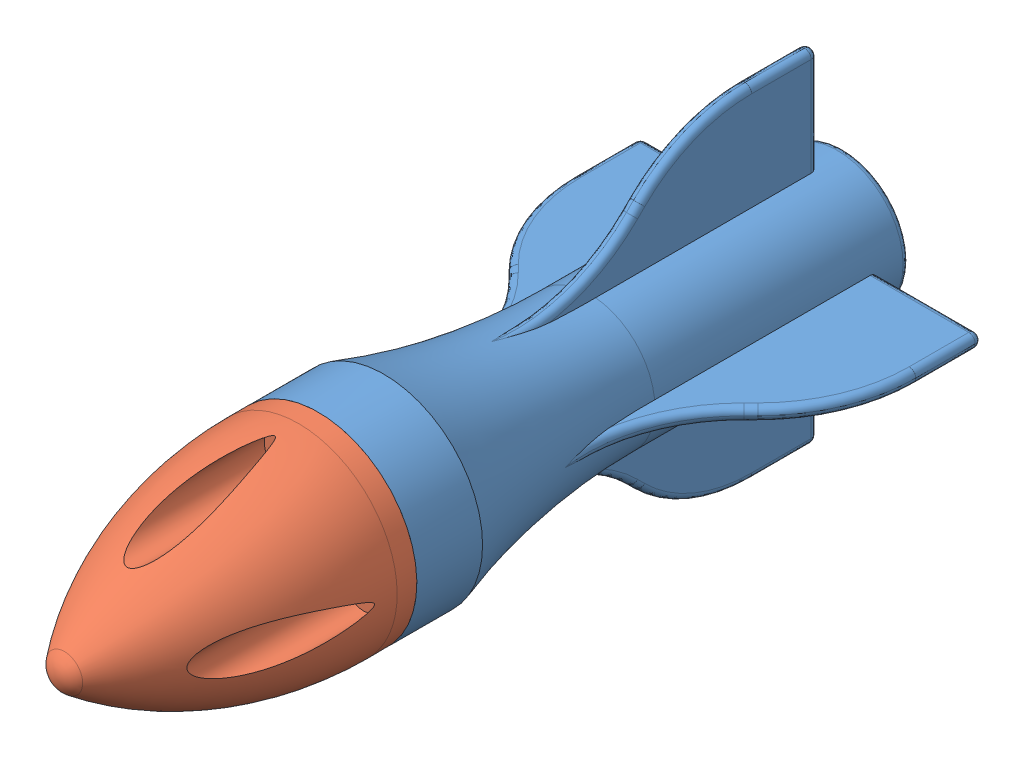
SolidWorks assembly MS-A-0043-TorpedoBodyAssem, configuration Default. Lengths in mm.
Overall size (65.99 65.99 152.4).
3 component instances, 3 part files, 3 mates.
Components (placement in the parent):
- MS-P-0042-Torpedo_Body-1: MS-P-0042-Torpedo_Body [Default] at (39.7527 50.552 32.0284) size (65.99 65.99 101.6)
- MS-P-0041-AltNoseCone-1: MS-P-0041-AltNoseCone [Default] at (39.7527 50.552 133.6284) x (0.018853 -0.999822 0) z (-0.999822 -0.018853 0) size (38.1 62.23 38.1)
- 9557K116_STEAM-RESISTANT EPDM O-RING-1: 9557K116_STEAM-RESISTANT EPDM O-RING [9557K116] at (39.7527 50.552 126.0084) x (0.997707 -0.067681 0) z (0 0 1) size (23.9 23.9 1.78)
Mates (geometry in assembly coordinates):
- Coincident1: coincident anti-aligned: plane of MS-P-0042-Torpedo Body (2)-1 through (39.7527 50.552 133.6284) normal (0 0 1); plane of MS-P-0041-AltNoseCone (1)-1 through (58.7993 50.9112 133.6284) normal (0 0 -1)
- Concentric1: concentric anti-aligned: cylinder of MS-P-0042-Torpedo Body (2)-1 through (39.7527 50.552 120.9284) axis (0 0 1) radius 19.05; cylinder of MS-P-0041-AltNoseCone (1)-1 through (39.7527 50.552 133.6284) axis (0 0 -1) radius 19.05
- Distance4: distance = 1.27 mm aligned: plane of 9557K116_STEAM-RESISTANT EPDM O-RING-1 through (39.7527 50.552 126.0084) normal (0 0 1); plane of MS-P-0042-Torpedo Body (2)-1 through (39.7527 50.552 124.7384) normal (0 0 1)
